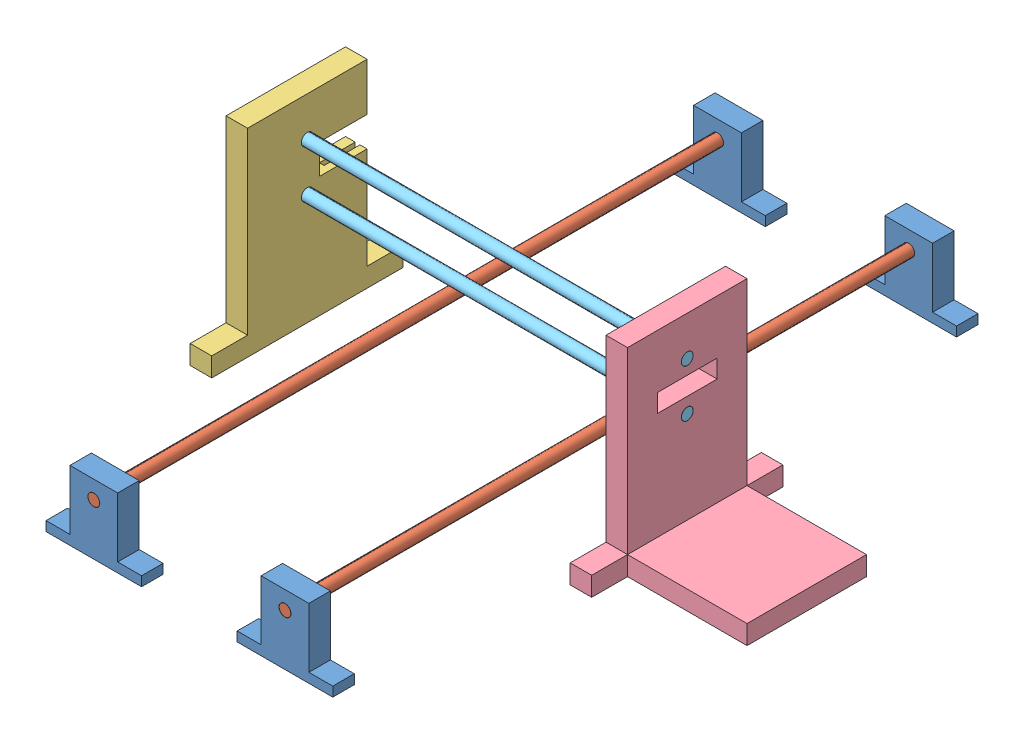
SolidWorks assembly 2D Plot structure, configuration Défaut. Lengths in mm.
Overall size (218 83 270).
10 component instances, 5 part files, 17 mates.
Components (placement in the parent):
- Pièce1-6: Pièce1 [Défaut] at (49.2725 -7.8577 44.5) size (40 29 9)
- Pièce1-8: Pièce1 [Défaut] at (129.2725 -7.8577 44.5) size (40 29 9)
- Pièce1-9: Pièce1 [Défaut] at (129.2725 -7.8577 305.5) size (40 29 9)
- Pièce1-10: Pièce1 [Défaut] at (49.2725 -7.8577 305.5) size (40 29 9)
- barre de guidage-3: barre de guidage [Défaut] at (69.2725 13.6423 35.5) size (4.9 4.9 270)
- barre de guidage-5: barre de guidage [Défaut] at (-10.7275 13.6423 35.5) size (4.9 4.9 270)
- X pièce for pulley-4: X pièce for pulley [Défaut] at (-51.7275 -7.8577 216.7066) x (0 0 -1) z (1 0 0) size (80 83 9)
- X pièce-1: X pièce [Défaut] at (107.2725 -7.8577 216.7066) x (0 0 -1) z (1 0 0) size (80 83 59)
- barre de guidage X axes-1: barre de guidage X axes [Défaut] at (-60.7275 58.6423 175.1534) x (0 0 -1) z (1 0 0) size (4.9 4.9 168)
- barre de guidage X axes-2: barre de guidage X axes [Défaut] at (107.2725 38.6423 175.1534) x (0 0 1) z (-1 0 0) size (4.9 4.9 168)
Mates (geometry in assembly coordinates):
- Coïncidente7: coincident aligned: line of Pièce1-6 through (9.2725 -7.8577 44.5) axis (-1 0 0); line of Pièce1-8 through (89.2725 -7.8577 44.5) axis (-1 0 0)
- Distance2: distance = 40 mm: point of Pièce1-6; point of Pièce1-8
- Coïncidente9: coincident aligned: line of Pièce1-8 through (89.2725 -7.8577 35.5) axis (0 0 1); line of Pièce1-9 through (89.2725 -7.8577 296.5) axis (0 0 1)
- Coïncidente10: coincident aligned: line of Pièce1-6 through (-30.7275 -7.8577 35.5) axis (0 0 1); line of Pièce1-10 through (-30.7275 -7.8577 296.5) axis (0 0 1)
- Coaxiale1: concentric aligned: circle of Pièce1-9; circle of barre de guidage-3
- Coïncidente15: coincident aligned: plane of Pièce1-8 through (129.2725 -7.8577 35.5) normal (0 0 -1); plane of barre de guidage-3 through (69.2725 13.6423 35.5) normal (0 0 -1)
- Coïncidente19: coincident aligned: plane of Pièce1-9 through (129.2725 -7.8577 305.5) normal (0 0 1); plane of barre de guidage-3 through (69.2725 13.6423 305.5) normal (0 0 1)
- Coïncidente24: coincident aligned: plane of Pièce1-6 through (49.2725 -7.8577 35.5) normal (0 0 -1); plane of barre de guidage-5 through (-10.7275 13.6423 35.5) normal (0 0 -1)
- Coaxiale4: concentric aligned: circle of Pièce1-6; circle of barre de guidage-5
- Coïncidente25: coincident aligned: plane of Pièce1-10 through (49.2725 -7.8577 305.5) normal (0 0 1); plane of barre de guidage-5 through (-10.7275 13.6423 305.5) normal (0 0 1)
- Distance5: distance = 150 mm: line of X pièce-1 through (98.2725 -7.8577 215.1534) axis (0 0 -1); line of X pièce for pulley-4 through (-51.7275 -7.8577 215.1534) axis (0 0 -1)
- Distance26: distance = 30 mm: line of X pièce for pulley-4 through (-60.7275 -7.8577 215.1534) axis (0 0 -1); line of Pièce1-10 through (-30.7275 -7.8577 296.5) axis (0 0 1)
- Parallèle9: parallel anti-aligned: line of Pièce1-9 through (89.2725 -7.8577 296.5) axis (0 0 1); line of X pièce-1 through (107.2725 -7.8577 215.1534) axis (0 0 -1)
- Coaxiale5: concentric aligned: circle of X pièce for pulley-4; circle of barre de guidage X axes-1
- Coïncidente67: coincident aligned: plane of X pièce-1 through (107.2725 -7.8577 216.7066) normal (1 0 0); plane of barre de guidage X axes-1 through (107.2725 58.6423 175.1534) normal (1 0 0)
- Coaxiale6: concentric anti-aligned: circle of X pièce for pulley-4; circle of barre de guidage X axes-2
- Coïncidente68: coincident aligned: plane of X pièce for pulley-4 through (-60.7275 -7.8577 216.7066) normal (-1 0 0); plane of barre de guidage X axes-2 through (-60.7275 38.6423 175.1534) normal (-1 0 0)
